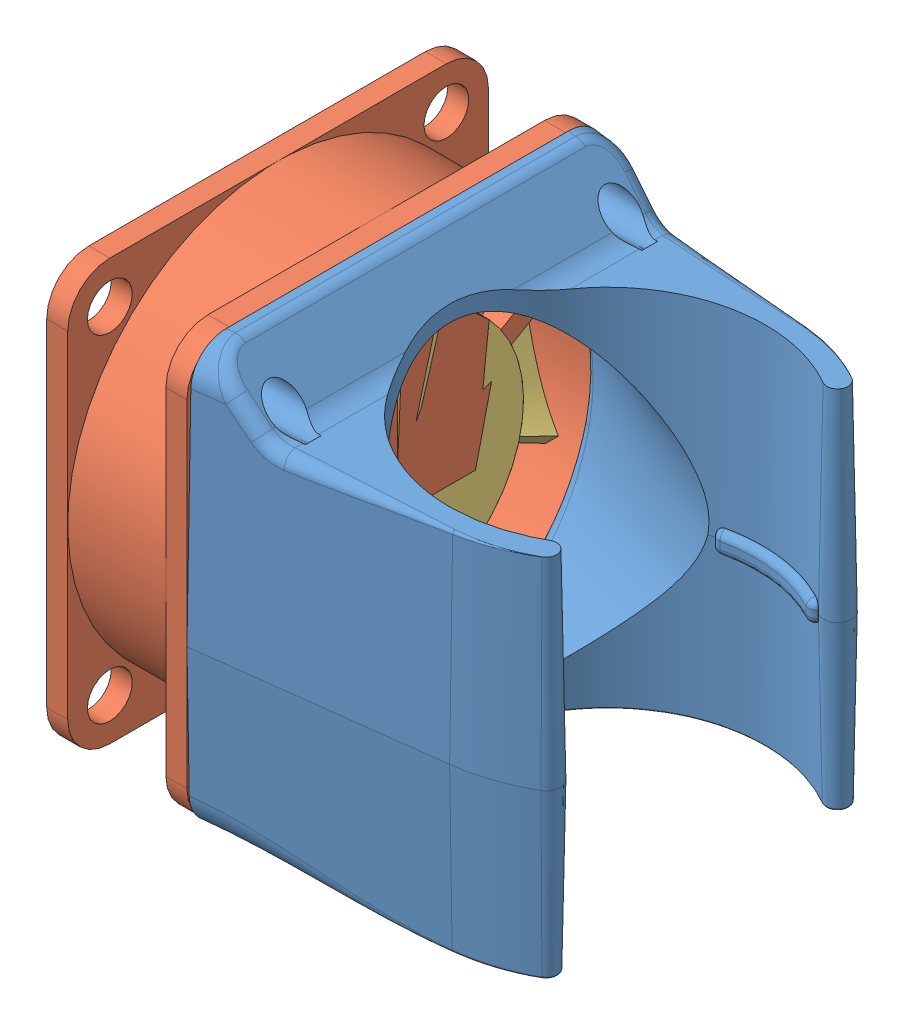
SolidWorks assembly fanduct, configuration Default. Lengths in mm.
Overall size (32 39.46 39.45).
4 component instances, 3 part files, 3 mates.
Components (placement in the parent):
- fan duct-1: fan duct [Default] at (6.8279 2.6216 26.4875) size (22.41 30.18 30)
- fan-1: fan [Default] at (15.7816 1.6787 26.8895) x (0 0 1) z (-1 0 0) size (39.45 39.46 10)
  - fan sub1-1: fan sub1 [Default] at (-0.402 15.9429 23.9537) size (30 30 10)
  - fan sub2-1: fan sub2 [Default] at (-0.402 15.9429 33.9537) x (0 0 1) z (-0.65899 0.752151 0) size (8.5 27.91 28)
Mates (geometry in assembly coordinates):
- Concentric1: concentric anti-aligned: cone of fan duct-1 through (-8.1721 29.6216 38.4875) axis (1 0 0); cylinder of fan-1/fan sub1-1 through (-9.6721 29.6216 38.4875) axis (-1 0 0) radius 1.6
- Concentric2: concentric anti-aligned: cone of fan duct-1 through (-8.1721 5.6216 14.4875) axis (1 0 0); cylinder of fan-1/fan sub1-1 through (-9.6721 5.6216 14.4875) axis (-1 0 0) radius 1.6
- Coincident1: coincident anti-aligned: plane of fan duct-1 through (-8.1721 2.6216 11.4875) normal (-1 0 0); plane of fan-1/fan sub1-1 through (-8.1721 17.6216 26.4875) normal (1 0 0)
